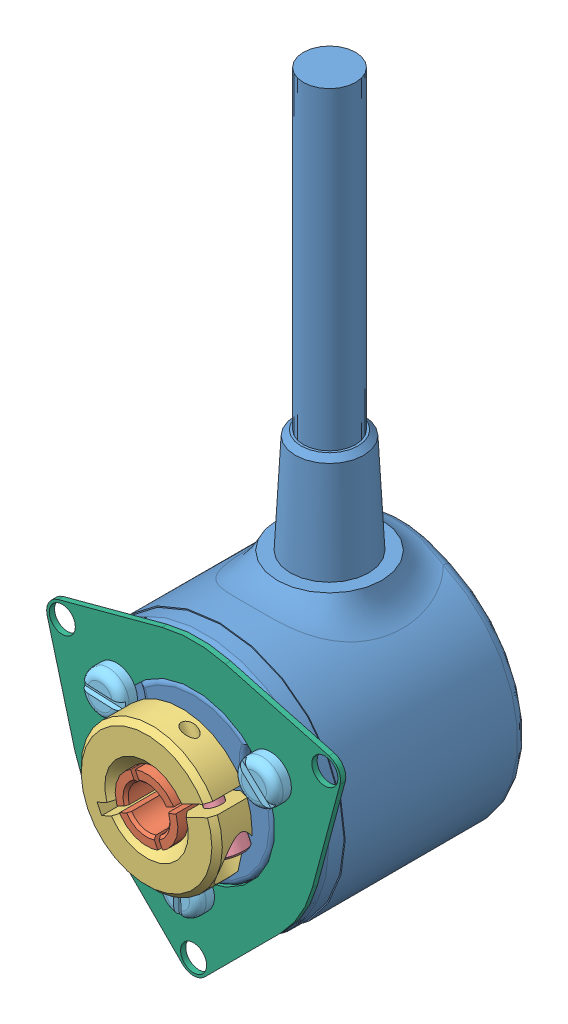
SolidWorks assembly Codeur_2MRH, configuration Default. Lengths in mm.
Overall size (38.09 70.8 24.5).
8 component instances, 6 part files, 16 mates.
Components (placement in the parent):
- corps_codeur_2MRH-1: corps_codeur_2MRH [Default] at (3.2886 -2.5929 -14.3048) size (24 64.75 20.04)
- mandrin_codeur_2MRH-1: mandrin_codeur_2MRH [Default] at (3.2886 -2.5929 -3.8048) x (-0.434638 0.900605 0) z (0 0 1) size (6 6 14)
- bague_codeur_2MRH-1: bague_codeur_2MRH [Default] at (3.2886 -2.5929 5.6952) x (0.434638 -0.900605 0) z (0 0 1) size (13.5 13.48 4.5)
- Vis_CHC_M2_L5-1: Vis_CHC_M2_L5 [B18.3.1M - 1.6 x 0.35 x 5 Hex SHCS -- 5NHX] at (9.1066 -4.3376 7.9452) x (-0.434638 0.900605 0) z (0 0 1) size (6.6 3 3)
- Vis_fendue_tete_bombee_M2_L5-1: Vis_fendue_tete_bombee_M2_L5 [B18.6.7M - M2 x 0.4 x 4 Slotted PHMS --4N] at (10.6498 1.6571 7.2952) x (0 0 -1) z (0.728333 -0.685223 0) size (5.65 4 4)
- Vis_fendue_tete_bombee_M2_L5-2: Vis_fendue_tete_bombee_M2_L5 [B18.6.7M - M2 x 0.4 x 4 Slotted PHMS --4N] at (-4.0726 1.6571 7.2952) x (0 0 -1) z (0.998972 -0.045336 0) size (5.65 4 4)
- Vis_fendue_tete_bombee_M2_L5-3: Vis_fendue_tete_bombee_M2_L5 [B18.6.7M - M2 x 0.4 x 4 Slotted PHMS --4N] at (3.2886 -11.0929 7.2952) x (0 0 -1) z (-0.043781 0.999041 0) size (5.65 4 4)
- Bride_membrane-1: Bride_membrane [Default] at (3.2886 -2.5929 5.6952) x (0.5 0.866025 0) z (-0.866025 0.5 0) size (28.11 0.5 27.75)
Mates (geometry in assembly coordinates):
- Coaxiale2: concentric anti-aligned: cylinder of corps_codeur_2MRH-1; cylinder of mandrin_codeur_2MRH-1
- Coïncidente1: coincident anti-aligned: plane of corps_codeur_2MRH-1 through (3.2886 -2.5929 -3.8048) normal (0 0 1); plane of mandrin_codeur_2MRH-1 through (3.2886 -2.5929 -3.8048) normal (0 0 -1)
- Coïncidente2: coincident anti-aligned: plane of corps_codeur_2MRH-1 through (3.2886 -2.5929 5.6952) normal (0 0 1); plane of bague_codeur_2MRH-1 through (3.2886 -2.5929 5.6952) normal (0 0 -1)
- Coaxiale3: concentric aligned: cylinder of mandrin_codeur_2MRH-1; cylinder of bague_codeur_2MRH-1
- Parallèle1: parallel aligned: plane of mandrin_codeur_2MRH-1 through (3.4051 -2.2591 0.1952) normal (0.434638 -0.900605 0); plane of bague_codeur_2MRH-1 through (9.1337 0.7831 5.6942) normal (0.434638 -0.900605 0)
- Coaxiale41: concentric anti-aligned: cylinder of bague_codeur_2MRH-1; cylinder of Vis_CHC_M2_L5-1
- Coïncidente41: coincident anti-aligned: plane of bague_codeur_2MRH-1 through (8.4112 -2.8966 7.9452) normal (0.434638 -0.900605 0); plane of Vis_CHC_M2_L5-1 through (7.0603 -3.5486 7.9452) normal (-0.434638 0.900605 0)
- Coaxiale81: concentric aligned: cylinder of corps_codeur_2MRH-1; cylinder of Vis_fendue_tete_bombee_M2_L5-1
- Coaxiale91: concentric aligned: cylinder of corps_codeur_2MRH-1; cylinder of Vis_fendue_tete_bombee_M2_L5-2
- Coaxiale101: concentric aligned: cylinder of corps_codeur_2MRH-1; cylinder of Vis_fendue_tete_bombee_M2_L5-3
- Coïncidente102: coincident anti-aligned: plane of corps_codeur_2MRH-1 through (3.2886 -2.5929 5.1952) normal (0 0 1); plane of Bride_membrane-1 through (3.2886 -2.5929 5.1952) normal (0 0 -1)
- Coïncidente103: coincident aligned: circle of corps_codeur_2MRH-1; cylinder of Bride_membrane-1
- Coaxiale102: concentric aligned: cylinder of corps_codeur_2MRH-1; cylinder of Bride_membrane-1
- Coïncidente104: coincident anti-aligned: plane of Vis_fendue_tete_bombee_M2_L5-2 through (-4.0273 2.6561 5.6952) normal (0 0 -1); plane of Bride_membrane-1 through (3.2886 -2.5929 5.6952) normal (0 0 1)
- Coïncidente105: coincident anti-aligned: plane of Vis_fendue_tete_bombee_M2_L5-1 through (11.335 2.3854 5.6952) normal (0 0 -1); plane of Bride_membrane-1 through (3.2886 -2.5929 5.6952) normal (0 0 1)
- Coïncidente106: coincident anti-aligned: plane of Vis_fendue_tete_bombee_M2_L5-3 through (2.2896 -11.1367 5.6952) normal (0 0 -1); plane of Bride_membrane-1 through (3.2886 -2.5929 5.6952) normal (0 0 1)
